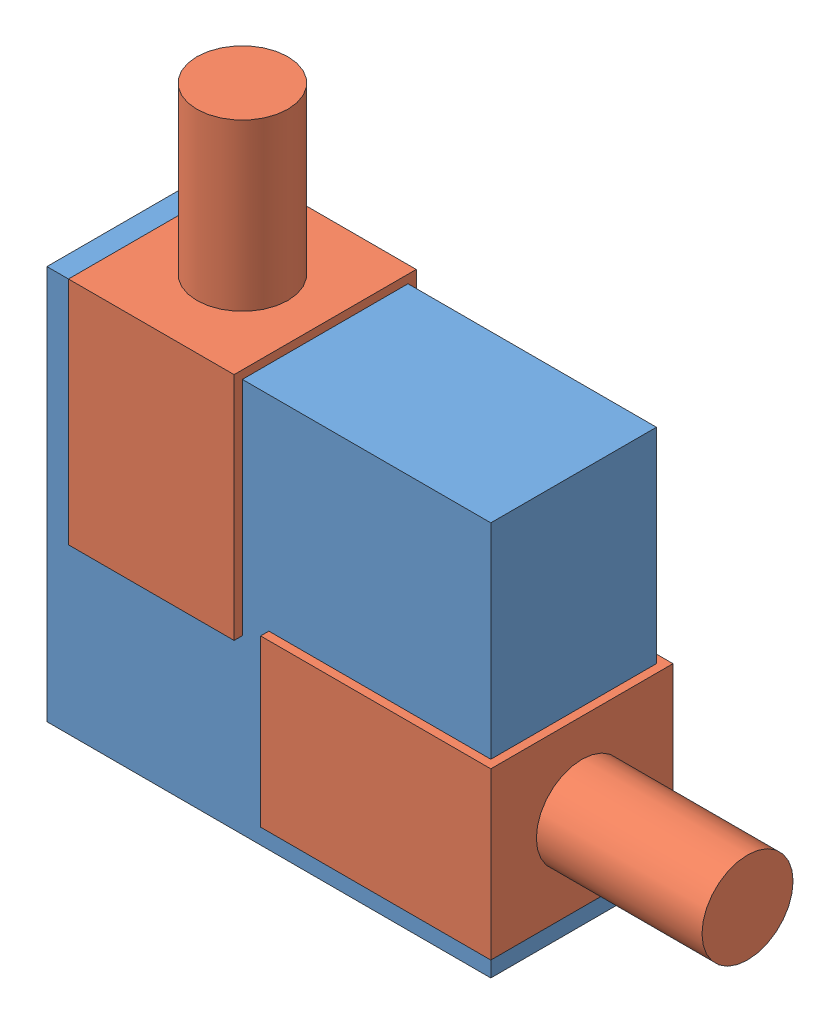
SolidWorks assembly task 2 - Robot Joint, configuration Default. Lengths in mm.
Overall size (74.6 68.6 22).
3 component instances, 2 part files, 5 mates.
Components (placement in the parent):
- motor robot2-1: motor robot2 [Default] at (7.0291 23.8593 40.7848) size (53.6 47.6 20)
- robot2 joint 2-1: robot2 joint 2 [Default] at (33.8291 2.9339 48.2954) x (0 0 -1) z (1 0 0) size (22 20 47.8)
- robot2 joint 2-2: robot2 joint 2 [Default] at (3.8288 47.6593 48.2954) x (0 0 -1) z (0 1 0) size (22 20 47.8)
Mates (geometry in assembly coordinates):
- Coincident13: coincident: line of motor robot2-1 through (33.8291 0.0593 60.7848) axis (0 1 0); line of robot2 joint 2-1 through (33.8291 22.9339 60.7848) axis (0 -1 0)
- Parallel5: parallel: plane of motor robot2-1 through (7.0291 23.8593 60.7848) normal (0 0 1); plane of robot2 joint 2-1 through (33.8291 22.9339 40.7848) normal (0 0 1)
- Coincident15: coincident: plane of motor robot2-1 through (33.8291 47.6593 60.7848) normal (1 0 0); plane of robot2 joint 2-1 through (33.8291 22.9339 60.7848) normal (-1 0 0)
- Coincident16: coincident: plane of motor robot2-1 through (7.0291 23.8593 60.7848) normal (0 0 1); plane of robot2 joint 2-2 through (-16.1712 20.8593 60.7848) normal (0 0 -1)
- Coincident17: coincident: plane of motor robot2-1 through (-19.7709 47.6593 60.7848) normal (0 1 0); plane of robot2 joint 2-2 through (-16.1712 47.6593 60.7848) normal (0 -1 0)
